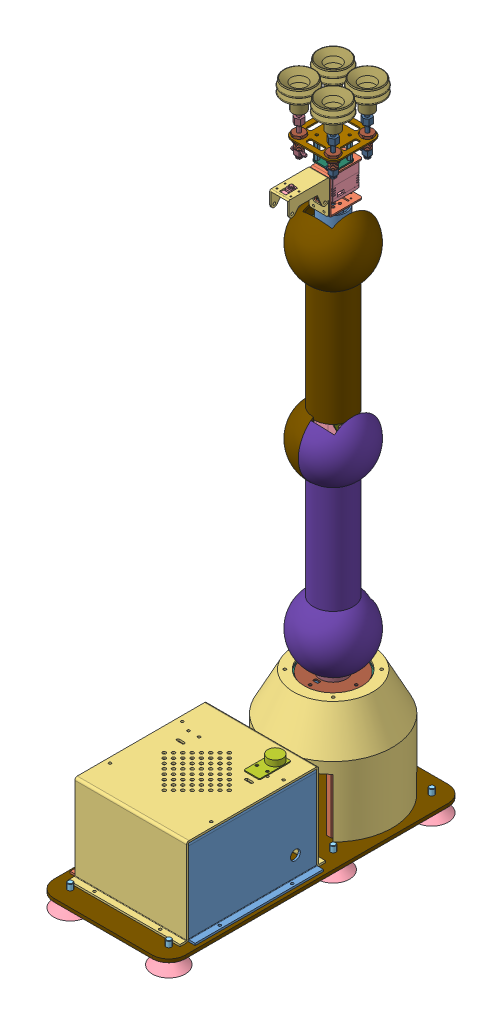
SolidWorks assembly 机械臂2.0, configuration 默认. Lengths in mm.
Overall size (254.56 968.05 483.5).
177 component instances, 43 part files, 19 mates.
Components (placement in the parent):
- base-1: base [默认] at origin size (174 161 174)
  - 1号舵机底座-1: 1号舵机底座 [默认] at (0 103 0) size (174 3 174)
  - M8×100铜柱-1: M8×100铜柱 [默认] at (-53.9281 0 -53.9802) size (15.01 100 13)
  - M8×100铜柱-2: M8×100铜柱 [默认] at (52.1379 0 52.0858) size (15.01 100 13)
  - M8×100铜柱-3: M8×100铜柱 [默认] at (52.1379 0 -53.9802) size (15.01 100 13)
  - M8×100铜柱-4: M8×100铜柱 [默认] at (-53.9281 0 52.0858) size (15.01 100 13)
  - 云台外壳-1: 云台外壳 [默认] at (0 161 0) x (0.707107 0 0.707107) z (-0.707107 0 0.707107) size (180 164 180)
  - 舵机-2: 舵机 [默认] at (0 103.2 -9.65) x (0 0 1) z (-1 0 0) size (40 51.4 20)
  - 轴承外顶-1: 轴承外顶 [默认] at (0 161 0) size (120 2 120)
  - 轴承-1: 轴承 [默认] at (0 149 0) x (0.957428 0 0.288672) z (-0.288672 0 0.957428) size (100 10 100)
  - 轴承外底座-1: 轴承外底座 [默认] at (0 149 0) size (120 2 120)
  - M3×40铜柱-1: M3×40铜柱 [默认] at (-36.7696 107 -36.7696) size (5.43 40 4.7)
  - M3×40铜柱-2: M3×40铜柱 [默认] at (36.7696 107 36.7696) size (5.43 40 4.7)
  - M3×40铜柱-3: M3×40铜柱 [默认] at (36.7696 107 -36.7696) size (5.43 40 4.7)
  - M3×40铜柱-4: M3×40铜柱 [默认] at (-36.7696 107 36.7696) size (5.43 40 4.7)
  - M3×4铜柱-1: M3×4铜柱 [默认] at (-36.7696 103 36.7696) size (5.43 4 4.7)
  - M3×4铜柱-2: M3×4铜柱 [默认] at (-36.7696 103 -36.7696) size (5.43 4 4.7)
  - M3×4铜柱-3: M3×4铜柱 [默认] at (36.7696 103 36.7696) size (5.43 4 4.7)
  - M3×4铜柱-4: M3×4铜柱 [默认] at (36.7696 103 -36.7696) size (5.43 4 4.7)
- shoulder-1: shoulder [默认] at (0 144 0) x (-1 0 0) z (0 0 -1) size (84 84 85)
  - 轴承底座-1: 轴承底座 [默认] at (0 5 0) size (82 2 84)
  - 轴承顶-1: 轴承顶 [默认] at (0 17 0) size (84 2 84)
  - 主舵盘-1: 主舵盘 [默认] at origin size (20 5 20)
  - 12号舵机连接管-1: 12号舵机连接管 [默认] at (0 17 0) x (0 0 1) z (-1 0 0) size (40 25 40)
  - 大U支架-1: 大U支架 [默认] at (0 44 0) size (51.6 42 40)
- upper-1: upper [默认] at (-20 227.65 0) x (0 -1 0) z (0 0 1) size (342.08 106 100.99)
  - 舵机-1: 舵机 [默认] at origin size (43.48 52.6 27.66)
    - 舵机-1: 舵机 [默认] at origin size (40 51.4 20)
    - 副舵盘-1: 副舵盘 [默认] at (9.65 -0.8 0) x (-0.933258 0 -0.359207) z (-0.359207 0 0.933258) size (20 5 20)
    - 主舵盘-1: 主舵盘 [默认] at (9.65 40.8 0) x (0.838844 0 0.544372) z (-0.544372 0 0.838844) size (20 5 20)
  - 短U支架-1: 短U支架 [默认] at (-28 20 0) x (0 1 0) z (0 0 -1) size (44 22 40)
  - 23号舵机连接管-1: 23号舵机连接管 [默认] at (-30 20 0) x (0 1 0) z (0 0 1) size (106 342.08 100.99)
  - 大U支架-1: 大U支架 [默认] at (-210.35 20 0) x (0 1 0) z (0 0 1) size (51.6 42 40)
- forearm-1: forearm [默认] at (-20 477.65 0) x (0 -1 0) z (0 0 1) size (350.08 106 100.99)
  - 舵机-1: 舵机 [默认] at origin size (43.48 52.6 27.66)
    - 舵机-1: 舵机 [默认] at origin size (40 51.4 20)
    - 副舵盘-1: 副舵盘 [默认] at (9.65 -0.8 0) x (-0.933258 0 -0.359207) z (-0.359207 0 0.933258) size (20 5 20)
    - 主舵盘-1: 主舵盘 [默认] at (9.65 40.8 0) x (0.838844 0 0.544372) z (-0.544372 0 0.838844) size (20 5 20)
  - 短U支架-1: 短U支架 [默认] at (-28 20 0) x (0 -1 0) z (0 0 1) size (44 22 40)
  - 34号舵机连接管-1: 34号舵机连接管 [默认] at (-208.35 20 0) x (0 -1 0) z (0 0 1) size (106 350.08 100.99)
  - 大U支架-1: 大U支架 [默认] at (-210.35 20 0) x (0 1 0) z (0 0 1) size (51.6 42 40)
- wrist-1: wrist [默认] at (-20 727.65 0) x (0 -1 0) z (0 0 1) size (129.18 52.6 112.65)
  - 舵机-1: 舵机 [默认] at origin size (43.48 52.6 27.66)
    - 舵机-1: 舵机 [默认] at origin size (40 51.4 20)
    - 副舵盘-1: 副舵盘 [默认] at (9.65 -0.8 0) x (-0.933258 0 -0.359207) z (-0.359207 0 0.933258) size (20 5 20)
    - 主舵盘-1: 主舵盘 [默认] at (9.65 40.8 0) x (0.838844 0 0.544372) z (-0.544372 0 0.838844) size (20 5 20)
  - 短U支架-1: 短U支架 [默认] at (-28 20 0) x (0 1 0) z (0 0 -1) size (44 22 40)
  - 45号舵机连接管-1: 45号舵机连接管 [默认] at (-48 20 0) x (0 -1 0) z (0 0 1) size (40 18 40)
  - 转向舵机支架-1: 转向舵机支架 [默认] at (-75 20 18) x (1 0 0) z (0 -1 0) size (54 50.65 29)
  - 舵机-2: 舵机 [默认] at (-60 20 -9.65) x (0 0 1) z (0 -1 0) size (40 51.4 20)
  - 摄像头支架-1: 摄像头支架 [默认] at (-75 20 22) x (-1 0 0) z (0 1 0) size (52 62 29)
  - 摄像头-1: 摄像头 [默认] at (-99 20 65) x (0 -1 0) z (0 0 -1) size (25 9.2 28)
    - 摄像头-1: 摄像头 [默认] at origin size (25 9.2 28)
    - 0603电容-2: 0603电容 [默认] at (-25.6955 -0.01 -49.0268) x (1 0 0) z (0 -1 0) size (1.6 0.82 0.82)
      - C_0603^0603电容-1: C_0603^0603电容 [默认] at (34.005 43.815 0) x (-1 0 0) z (0 0 1) size (1.6 0.82 0.82) (virtual)
        - C_0603-9^C_0603_0603电容-1: C_0603-9^C_0603_0603电容 [默认] at origin size (1.6 0.82 0.82) (virtual)
    - 0603电容-3: 0603电容 [默认] at (-42.3062 -0.01 -47.0667) x (1 0 0) z (0 -1 0) size (1.6 0.82 0.82)
      - C_0603^0603电容-1: C_0603^0603电容 [默认] at (34.005 43.815 0) x (-1 0 0) z (0 0 1) size (1.6 0.82 0.82) (virtual)
        - C_0603-9^C_0603_0603电容-1: C_0603-9^C_0603_0603电容 [默认] at origin size (1.6 0.82 0.82) (virtual)
    - 0603电容-7: 0603电容 [默认] at (49.2456 -0.01 -38.1328) x (0 0 1) z (0 -1 0) size (1.6 0.82 0.82)
      - C_0603^0603电容-1: C_0603^0603电容 [默认] at (34.005 43.815 0) x (-1 0 0) z (0 0 1) size (1.6 0.82 0.82) (virtual)
        - C_0603-9^C_0603_0603电容-1: C_0603-9^C_0603_0603电容 [默认] at origin size (1.6 0.82 0.82) (virtual)
    - 0603电容-10: 0603电容 [默认] at (-25.4606 -0.01 -42.7048) x (1 0 0) z (0 -1 0) size (1.6 0.82 0.82)
      - C_0603^0603电容-1: C_0603^0603电容 [默认] at (34.005 43.815 0) x (-1 0 0) z (0 0 1) size (1.6 0.82 0.82) (virtual)
        - C_0603-9^C_0603_0603电容-1: C_0603-9^C_0603_0603电容 [默认] at origin size (1.6 0.82 0.82) (virtual)
    - 0603电容-12: 0603电容 [默认] at (-26.2671 -0.01 -53.9256) x (1 0 0) z (0 -1 0) size (1.6 0.82 0.82)
      - C_0603^0603电容-1: C_0603^0603电容 [默认] at (34.005 43.815 0) x (-1 0 0) z (0 0 1) size (1.6 0.82 0.82) (virtual)
        - C_0603-9^C_0603_0603电容-1: C_0603-9^C_0603_0603电容 [默认] at origin size (1.6 0.82 0.82) (virtual)
    - 0805电容-1: 0805电容 [默认] at (51.4431 -0.01 78.819) x (-1 0 0) z (0 -1 0) size (1.22 2 0.52)
      - C_0805^0805电容-1: C_0805^0805电容 [默认] at (59.563 77.597 0) x (0 1 0) z (0 0 1) size (2 1.22 0.52) (virtual)
        - C_0805-5^C_0805_0805电容-1: C_0805-5^C_0805_0805电容 [默认] at origin size (2 1.22 0.52) (virtual)
    - 0805电阻-1: 0805电阻 [默认] at (115.7364 0 -119.6397) x (0 0 1) z (0 -1 0) size (1.25 2 0.5)
      - R_0805^0805电阻-1: R_0805^0805电阻 [默认] at (112.776 107.442 0) x (0 1 0) z (0 0 1) size (2 1.25 0.5) (virtual)
        - R_0805-21^R_0805_0805电阻-1: R_0805-21^R_0805_0805电阻 [默认] at origin size (2 1.25 0.5) (virtual)
    - 0603电阻-3: 0603电阻 [默认] at (118.0517 0 -149.4378) x (0 0 1) z (0 -1 0) size (0.8 1.6 0.4)
      - R_0603^0603电阻-1: R_0603^0603电阻 [默认] at (138.684 113.411 0) x (0 1 0) z (0 0 1) size (1.6 0.8 0.4) (virtual)
        - R_0603-25^R_0603_0603电阻-1: R_0603-25^R_0603_0603电阻 [默认] at origin size (1.6 0.8 0.4) (virtual)
    - 0603电阻-4: 0603电阻 [默认] at (-106.3314 1 -147.3108) x (0 0 1) z (0 1 0) size (0.8 1.6 0.4)
      - R_0603^0603电阻-1: R_0603^0603电阻 [默认] at (138.684 113.411 0) x (0 1 0) z (0 0 1) size (1.6 0.8 0.4) (virtual)
        - R_0603-25^R_0603_0603电阻-1: R_0603-25^R_0603_0603电阻 [默认] at origin size (1.6 0.8 0.4) (virtual)
    - 0603电阻-5: 0603电阻 [默认] at (134.1937 0 114.6319) x (-1 0 0) z (0 -1 0) size (0.8 1.6 0.4)
      - R_0603^0603电阻-1: R_0603^0603电阻 [默认] at (138.684 113.411 0) x (0 1 0) z (0 0 1) size (1.6 0.8 0.4) (virtual)
        - R_0603-25^R_0603_0603电阻-1: R_0603-25^R_0603_0603电阻 [默认] at origin size (1.6 0.8 0.4) (virtual)
    - 0603电容-14: 0603电容 [默认] at (-26.2671 -0.01 -52.4256) x (1 0 0) z (0 -1 0) size (1.6 0.82 0.82)
      - C_0603^0603电容-1: C_0603^0603电容 [默认] at (34.005 43.815 0) x (-1 0 0) z (0 0 1) size (1.6 0.82 0.82) (virtual)
        - C_0603-9^C_0603_0603电容-1: C_0603-9^C_0603_0603电容 [默认] at origin size (1.6 0.82 0.82) (virtual)
    - 0603电容-15: 0603电容 [默认] at (-30.4606 -0.01 -42.7048) x (1 0 0) z (0 -1 0) size (1.6 0.82 0.82)
      - C_0603^0603电容-1: C_0603^0603电容 [默认] at (34.005 43.815 0) x (-1 0 0) z (0 0 1) size (1.6 0.82 0.82) (virtual)
        - C_0603-9^C_0603_0603电容-1: C_0603-9^C_0603_0603电容 [默认] at origin size (1.6 0.82 0.82) (virtual)
    - 0603电容-16: 0603电容 [默认] at (-35.4606 -0.01 -42.7048) x (1 0 0) z (0 -1 0) size (1.6 0.82 0.82)
      - C_0603^0603电容-1: C_0603^0603电容 [默认] at (34.005 43.815 0) x (-1 0 0) z (0 0 1) size (1.6 0.82 0.82) (virtual)
        - C_0603-9^C_0603_0603电容-1: C_0603-9^C_0603_0603电容 [默认] at origin size (1.6 0.82 0.82) (virtual)
    - 0603电容-17: 0603电容 [默认] at (-37.2671 -0.01 -53.9256) x (1 0 0) z (0 -1 0) size (1.6 0.82 0.82)
      - C_0603^0603电容-1: C_0603^0603电容 [默认] at (34.005 43.815 0) x (-1 0 0) z (0 0 1) size (1.6 0.82 0.82) (virtual)
        - C_0603-9^C_0603_0603电容-1: C_0603-9^C_0603_0603电容 [默认] at origin size (1.6 0.82 0.82) (virtual)
    - 0603电容-18: 0603电容 [默认] at (-37.2671 -0.01 -52.4256) x (1 0 0) z (0 -1 0) size (1.6 0.82 0.82)
      - C_0603^0603电容-1: C_0603^0603电容 [默认] at (34.005 43.815 0) x (-1 0 0) z (0 0 1) size (1.6 0.82 0.82) (virtual)
        - C_0603-9^C_0603_0603电容-1: C_0603-9^C_0603_0603电容 [默认] at origin size (1.6 0.82 0.82) (virtual)
    - 0805电阻-2: 0805电阻 [默认] at (104.7364 0 -119.6397) x (0 0 1) z (0 -1 0) size (1.25 2 0.5)
      - R_0805^0805电阻-1: R_0805^0805电阻 [默认] at (112.776 107.442 0) x (0 1 0) z (0 0 1) size (2 1.25 0.5) (virtual)
        - R_0805-21^R_0805_0805电阻-1: R_0805-21^R_0805_0805电阻 [默认] at origin size (2 1.25 0.5) (virtual)
    - 0603电容-19: 0603电容 [默认] at (-31.1955 -0.01 -49.0268) x (1 0 0) z (0 -1 0) size (1.6 0.82 0.82)
      - C_0603^0603电容-1: C_0603^0603电容 [默认] at (34.005 43.815 0) x (-1 0 0) z (0 0 1) size (1.6 0.82 0.82) (virtual)
        - C_0603-9^C_0603_0603电容-1: C_0603-9^C_0603_0603电容 [默认] at origin size (1.6 0.82 0.82) (virtual)
    - 0603电容-20: 0603电容 [默认] at (-36.6955 -0.01 -49.0268) x (1 0 0) z (0 -1 0) size (1.6 0.82 0.82)
      - C_0603^0603电容-1: C_0603^0603电容 [默认] at (34.005 43.815 0) x (-1 0 0) z (0 0 1) size (1.6 0.82 0.82) (virtual)
        - C_0603-9^C_0603_0603电容-1: C_0603-9^C_0603_0603电容 [默认] at origin size (1.6 0.82 0.82) (virtual)
    - 0603电容-21: 0603电容 [默认] at (43.7456 -0.01 -38.1328) x (0 0 1) z (0 -1 0) size (1.6 0.82 0.82)
      - C_0603^0603电容-1: C_0603^0603电容 [默认] at (34.005 43.815 0) x (-1 0 0) z (0 0 1) size (1.6 0.82 0.82) (virtual)
        - C_0603-9^C_0603_0603电容-1: C_0603-9^C_0603_0603电容 [默认] at origin size (1.6 0.82 0.82) (virtual)
    - 0603电容-22: 0603电容 [默认] at (38.2456 -0.01 -38.1328) x (0 0 1) z (0 -1 0) size (1.6 0.82 0.82)
      - C_0603^0603电容-1: C_0603^0603电容 [默认] at (34.005 43.815 0) x (-1 0 0) z (0 0 1) size (1.6 0.82 0.82) (virtual)
        - C_0603-9^C_0603_0603电容-1: C_0603-9^C_0603_0603电容 [默认] at origin size (1.6 0.82 0.82) (virtual)
    - 0603电阻-6: 0603电阻 [默认] at (132.6937 0 114.6319) x (-1 0 0) z (0 -1 0) size (0.8 1.6 0.4)
      - R_0603^0603电阻-1: R_0603^0603电阻 [默认] at (138.684 113.411 0) x (0 1 0) z (0 0 1) size (1.6 0.8 0.4) (virtual)
        - R_0603-25^R_0603_0603电阻-1: R_0603-25^R_0603_0603电阻 [默认] at origin size (1.6 0.8 0.4) (virtual)
- ee-1: ee [默认] at (0 828.45 0) x (0 0 -1) z (-1 0 0) size (103.52 114.99 102.45)
  - 吸盘支架-1: 吸盘支架 [默认] at (0 -37.5 0) size (75 2 75)
  - 继手-1: 继手 [默认] at (-26 -72.6 -26) size (49.38 104.71 49.38)
    - 继手1-1: 继手1 [默认] at origin size (13.86 62.71 16.6)
    - 继手2-2: 继手2 [默认] at (0 29.1 0) x (0.962822 0 0.270137) z (-0.270137 0 0.962822) size (19.63 21.32 17)
    - MP50吸盘-2: MP50吸盘 [默认] at (0 -15 0) size (49.38 42 49.38)
  - 三通继手-1: 三通继手 [默认] at (-26 -72.6 26) size (51.52 104.71 51.52)
    - 三通继手1-1: 三通继手1 [默认] at origin size (13.86 62.71 21.2)
    - 继手2-1: 继手2 [默认] at (0 29.1 0) size (19.63 21.32 17)
    - MP50吸盘-1: MP50吸盘 [默认] at (0 -15 0) x (0.999013 0 0.044422) z (-0.044422 0 0.999013) size (49.38 42 49.38)
  - 三通继手-2: 三通继手 [默认] at (26 -72.6 26) size (51.52 104.71 51.52)
    - 三通继手1-1: 三通继手1 [默认] at origin size (13.86 62.71 21.2)
    - 继手2-1: 继手2 [默认] at (0 29.1 0) size (19.63 21.32 17)
    - MP50吸盘-1: MP50吸盘 [默认] at (0 -15 0) x (0.999013 0 0.044422) z (-0.044422 0 0.999013) size (49.38 42 49.38)
  - 继手-2: 继手 [默认] at (26 -72.6 -26) size (49.38 104.71 49.38)
    - 继手1-1: 继手1 [默认] at origin size (13.86 62.71 16.6)
    - 继手2-2: 继手2 [默认] at (0 29.1 0) x (0.962822 0 0.270137) z (-0.270137 0 0.962822) size (19.63 21.32 17)
    - MP50吸盘-2: MP50吸盘 [默认] at (0 -15 0) size (49.38 42 49.38)
  - M4×30铜柱-1: M4×30铜柱 [默认] at (-12.5 -37.5 -12.5) size (6.93 30 6)
  - M4×30铜柱-2: M4×30铜柱 [默认] at (-12.5 -37.5 12.5) size (6.93 30 6)
  - M4×30铜柱-3: M4×30铜柱 [默认] at (12.5 -37.5 -12.5) size (6.93 30 6)
  - M4×30铜柱-4: M4×30铜柱 [默认] at (12.5 -37.5 12.5) x (0.5 0 -0.866025) z (0.866025 0 0.5) size (6.93 30 6)
  - 负载连接板-2: 负载连接板 [默认] at (0 -5.5 0) size (33 4.5 33)
  - hexagon socket button head screws gb-1: hexagon socket button head screws gb [GB_SOCKET_TYPE7 M4X16-N] at (12.5 -3.3 12.5) x (0 -1 0) z (0 0 1) size (18.2 7.6 7.6)
  - hexagon socket button head screws gb-2: hexagon socket button head screws gb [GB_SOCKET_TYPE7 M4X16-N] at (12.5 -3.3 -12.5) x (0 -1 0) z (0 0 1) size (18.2 7.6 7.6)
  - hexagon socket button head screws gb-3: hexagon socket button head screws gb [GB_SOCKET_TYPE7 M4X16-N] at (-12.5 -3.3 -12.5) x (0 -1 0) z (0 0 1) size (18.2 7.6 7.6)
  - hexagon socket button head screws gb-4: hexagon socket button head screws gb [GB_SOCKET_TYPE7 M4X16-N] at (-12.5 -3.3 12.5) x (0 -1 0) z (0 0 1) size (18.2 7.6 7.6)
  - 镙丝 PM2x8-半圆头-1: 镙丝 PM2x8-半圆头 [默认] at (8 -8.7 0) x (-0.999997 0 -0.002253) z (-0.002253 0 0.999997) size (3.55 9.32 3.55)
  - 镙丝 PM2x8-半圆头-2: 镙丝 PM2x8-半圆头 [默认] at (-8 -8.7 0) x (-0.981299 0 0.192489) z (0.192489 0 0.981299) size (3.55 9.32 3.55)
  - 镙丝 PM2x8-半圆头-3: 镙丝 PM2x8-半圆头 [默认] at (-5.6569 -8.7 -5.6569) x (-0.317723 0 0.948184) z (0.948184 0 0.317723) size (3.55 9.32 3.55)
  - 镙丝 PM2x8-半圆头-4: 镙丝 PM2x8-半圆头 [默认] at (-5.6569 -8.7 5.6569) x (-0.996572 0 0.082729) z (0.082729 0 0.996572) size (3.55 9.32 3.55)
  - 镙丝 PM2x8-半圆头-5: 镙丝 PM2x8-半圆头 [默认] at (5.6569 -8.7 -5.6569) x (-0.951072 0 0.30897) z (0.30897 0 0.951072) size (3.55 9.32 3.55)
  - 镙丝 PM2x8-半圆头-6: 镙丝 PM2x8-半圆头 [默认] at (0 -8.7 8) x (-0.949174 0 0.314752) z (0.314752 0 0.949174) size (3.55 9.32 3.55)
  - 镙丝 PM2x8-半圆头-7: 镙丝 PM2x8-半圆头 [默认] at (5.6569 -8.7 5.6569) x (-0.981877 0 -0.18952) z (-0.18952 0 0.981877) size (3.55 9.32 3.55)
  - 镙丝 PM2x8-半圆头-8: 镙丝 PM2x8-半圆头 [默认] at (0 -8.7 -8) x (-0.861814 0 0.507224) z (0.507224 0 0.861814) size (3.55 9.32 3.55)
  - 主舵盘-1: 主舵盘 [默认] x (-0.707107 0 -0.707107) z (-0.707107 0 0.707107) size (20 5 20)
- 树莓派底座-1: 树莓派底座 [默认] at (0 0 125) x (0 0 1) z (-1 0 0) size (461.89 173.5 214.03)
  - 底座-1: 底座 [默认] at origin size (450 35 200)
  - 长边外壳2-1: 长边外壳2 [默认] at (82.5 65 -82) x (-1 0 0) z (0 1 0) size (195 23 130)
  - 长边外壳1-1: 长边外壳1 [默认] at (82.5 65 85) x (1 0 0) z (0 -1 0) size (195 23 130)
  - 顶盖-1: 顶盖 [默认] at (82.5 133 0) size (221 133 170)
  - 底座吸盘-1: 底座吸盘 [默认] at (-200 -14 75) x (0.97823 0 -0.207524) z (0.207524 0 0.97823) size (50 34 50)
    - 底座吸盘-1: 底座吸盘 [默认] at origin size (50 20 50)
    - hexagon socket countersunk head screws gb-2: hexagon socket countersunk head screws gb [GB_FASTENER_SCREWS_HSCHS M8X20-N] at (0 3 0) x (0 1 0) z (-0.546944 0 0.837169) size (20 15.24 15.24)
  - 底座吸盘-2: 底座吸盘 [默认] at (-200 -14 -75) x (0.965229 0 0.261404) z (-0.261404 0 0.965229) size (50 34 50)
    - 底座吸盘-1: 底座吸盘 [默认] at origin size (50 20 50)
    - hexagon socket countersunk head screws gb-2: hexagon socket countersunk head screws gb [GB_FASTENER_SCREWS_HSCHS M8X20-N] at (0 3 0) x (0 1 0) z (-0.546944 0 0.837169) size (20 15.24 15.24)
  - 底座吸盘-3: 底座吸盘 [默认] at (-50 -14 -75) x (0.994322 0 -0.106417) z (0.106417 0 0.994322) size (50 34 50)
    - 底座吸盘-1: 底座吸盘 [默认] at origin size (50 20 50)
    - hexagon socket countersunk head screws gb-2: hexagon socket countersunk head screws gb [GB_FASTENER_SCREWS_HSCHS M8X20-N] at (0 3 0) x (0 1 0) z (-0.546944 0 0.837169) size (20 15.24 15.24)
  - 底座吸盘-4: 底座吸盘 [默认] at (-50 -14 75) x (0.919595 0 0.392869) z (-0.392869 0 0.919595) size (50 34 50)
    - 底座吸盘-1: 底座吸盘 [默认] at origin size (50 20 50)
    - hexagon socket countersunk head screws gb-2: hexagon socket countersunk head screws gb [GB_FASTENER_SCREWS_HSCHS M8X20-N] at (0 3 0) x (0 1 0) z (-0.546944 0 0.837169) size (20 15.24 15.24)
  - 底座吸盘-5: 底座吸盘 [默认] at (200 -14 -75) x (0.95624 0 -0.292584) z (0.292584 0 0.95624) size (50 34 50)
    - 底座吸盘-1: 底座吸盘 [默认] at origin size (50 20 50)
    - hexagon socket countersunk head screws gb-2: hexagon socket countersunk head screws gb [GB_FASTENER_SCREWS_HSCHS M8X20-N] at (0 3 0) x (0 1 0) z (-0.546944 0 0.837169) size (20 15.24 15.24)
  - 底座吸盘-6: 底座吸盘 [默认] at (200 -14 75) x (0.984809 0 -0.17364) z (0.17364 0 0.984809) size (50 34 50)
    - 底座吸盘-1: 底座吸盘 [默认] at origin size (50 20 50)
    - hexagon socket countersunk head screws gb-2: hexagon socket countersunk head screws gb [GB_FASTENER_SCREWS_HSCHS M8X20-N] at (0 3 0) x (0 1 0) z (-0.546944 0 0.837169) size (20 15.24 15.24)
  - 显示屏-1: 显示屏 [默认] at (82.5 68.5 95.5) x (-1 0 0) z (0 1 0) size (165 17 109.5)
  - 语音合成模块-1: 语音合成模块 [默认] at (27 138 -52) size (48 10.5 24)
Mates (geometry in assembly coordinates):
- 重合1: coincident anti-aligned: plane of baselink-1/轴承-1 through (0 159 0) normal (0 1 0); plane of shoulder-1/轴承顶-1 through (0 159 0) normal (0 -1 0)
- 同心1: concentric aligned: circle of baselink-1/舵机-2; circle of shoulder_link-1/主舵盘-1
- 重合2: coincident anti-aligned: plane of shoulder-1/大U支架-1 through (-23.8 188 0) normal (1 0 0); plane of upper-1/舵机-1/副舵盘-1 through (-23.8 218 0) normal (-1 0 0)
- 同心2: concentric anti-aligned: circle of shoulder_link-1/大U支架-1; circle of upper_link-1/舵机-1/副舵盘-1
- 重合3: coincident anti-aligned: plane of upper-1/大U支架-1 through (23.8 438 0) normal (-1 0 0); plane of forearm-1/舵机-1/主舵盘-1 through (23.8 468 0) normal (1 0 0)
- 同心3: concentric anti-aligned: circle of upper_link-1/大U支架-1; circle of forearm_link-1/舵机-1/主舵盘-1
- 重合4: coincident anti-aligned: plane of forearm-1/大U支架-1 through (23.8 688 0) normal (-1 0 0); plane of wrist-1/舵机-1/主舵盘-1 through (23.8 718 0) normal (1 0 0)
- 同心4: concentric anti-aligned: circle of forearm_link-1/大U支架-1; circle of wrist_link-1/舵机-1/主舵盘-1
- 重合5: coincident anti-aligned: plane of wrist-1/舵机-2 through (0 828.45 0) normal (0 1 0); plane of ee-1/主舵盘-1 through (0 828.45 0) normal (0 -1 0)
- 同心5: concentric aligned: circle of wrist_link-1/舵机-2; circle of ee_link-1/主舵盘-1
- 重合6: coincident anti-aligned: plane of baselink-1/云台外壳-1 through (0 0 0) normal (0 -1 0); plane of 树莓派底座-1/底座-1 through (0 0 125) normal (0 1 0)
- 同心6: concentric aligned: circle of baselink-1/M8×100铜柱-1; circle of 树莓派底座-1/底座-1
- 同心7: concentric aligned: circle of baselink-1/M8×100铜柱-3; circle of 树莓派底座-1/底座-1
- 重合7: coordinate: unknown of baselink-1
- 平行1: parallel anti-aligned: plane of shoulder-1 through (0 144 0) normal (-1 0 0)
- 平行3: parallel anti-aligned: plane of upper-1 through (-20 227.65 0) normal (0 -1 0)
- 平行4: parallel anti-aligned: plane of forearm-1 through (-20 477.65 0) normal (0 -1 0)
- 平行5: parallel anti-aligned: plane of wrist-1 through (-20 727.65 0) normal (0 -1 0)
- 平行6: parallel anti-aligned: plane of ee-1 through (0 828.45 0) normal (0 0 -1)
